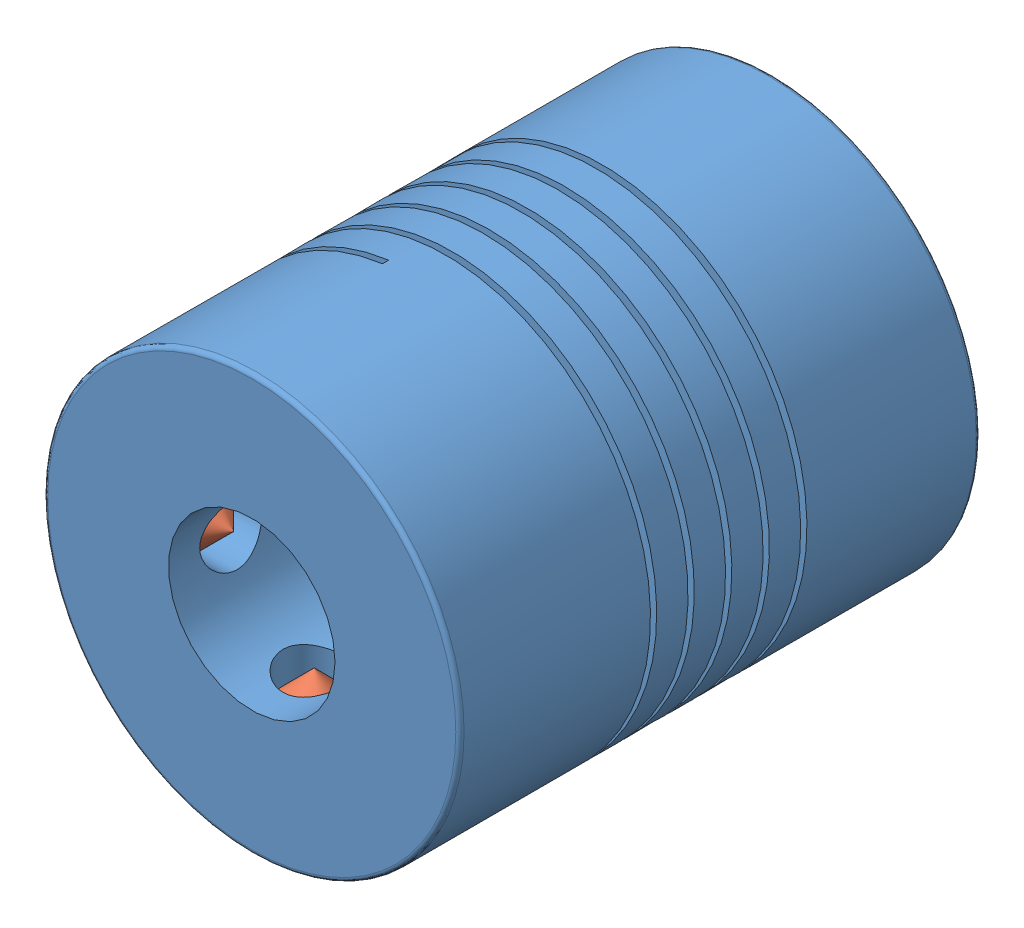
SolidWorks assembly Shaft Coupler 5mm 8mm, configuration Predeterminado. Lengths in mm.
Overall size (20.77 20.77 25).
5 component instances, 2 part files, 4 mates.
Components (placement in the parent):
- Shaft Coupler 5mm 8mm Body-1: Shaft Coupler 5mm 8mm Body [Predeterminado] at (-1.3837 -0.8648 0) size (20.77 20.77 25)
- socket set screw cone point_am-7: socket set screw cone point_am [B18.3.6M - M3 x 0.5 x 6 Hex Socket Cone Pt. SS --N] at (-11.2647 -0.8648 22) x (1 0 0) z (0 -0.164849 0.986319) size (6 3 3)
- socket set screw cone point_am-8: socket set screw cone point_am [B18.3.6M - M3 x 0.5 x 6 Hex Socket Cone Pt. SS --N] at (-11.1909 -0.8648 3) x (1 0 0) z (0 0.00677 0.999977) size (6 3 3)
- socket set screw cone point_am-9: socket set screw cone point_am [B18.3.6M - M3 x 0.5 x 6 Hex Socket Cone Pt. SS --N] at (-1.3837 -10.7654 3) x (0 1 0) z (-0.345086 0 0.938571) size (6 3 3)
- socket set screw cone point_am-10: socket set screw cone point_am [B18.3.6M - M3 x 0.5 x 6 Hex Socket Cone Pt. SS --N] at (-1.3837 -10.5992 22) x (0 1 0) z (-0.865685 0 0.500588) size (6 3 3)
Mates (geometry in assembly coordinates):
- Concéntrica7: concentric anti-aligned: cylinder of Shaft Coupler 5mm 8mm Body-1 through (-161.3837 -0.8648 22) axis (1 0 0) radius 1.5; cylinder of socket set screw cone point_am-7 through (-23.9647 -0.8648 22) axis (-1 0 0) radius 1.5
- Concéntrica8: concentric anti-aligned: cylinder of Shaft Coupler 5mm 8mm Body-1 through (-161.3837 -0.8648 3) axis (1 0 0) radius 1.5; cylinder of socket set screw cone point_am-8 through (-23.8909 -0.8648 3) axis (-1 0 0) radius 1.5
- Concéntrica10: concentric anti-aligned: cylinder of Shaft Coupler 5mm 8mm Body-1 through (-1.3837 -18.8648 3) axis (0 1 0) radius 1.5; cylinder of socket set screw cone point_am-9 through (-1.3837 -23.4654 3) axis (0 -1 0) radius 1.5
- Concéntrica11: concentric anti-aligned: cylinder of Shaft Coupler 5mm 8mm Body-1 through (-1.3837 -18.8648 22) axis (0 1 0) radius 1.5; cylinder of socket set screw cone point_am-10 through (-1.3837 -23.2992 22) axis (0 -1 0) radius 1.5
